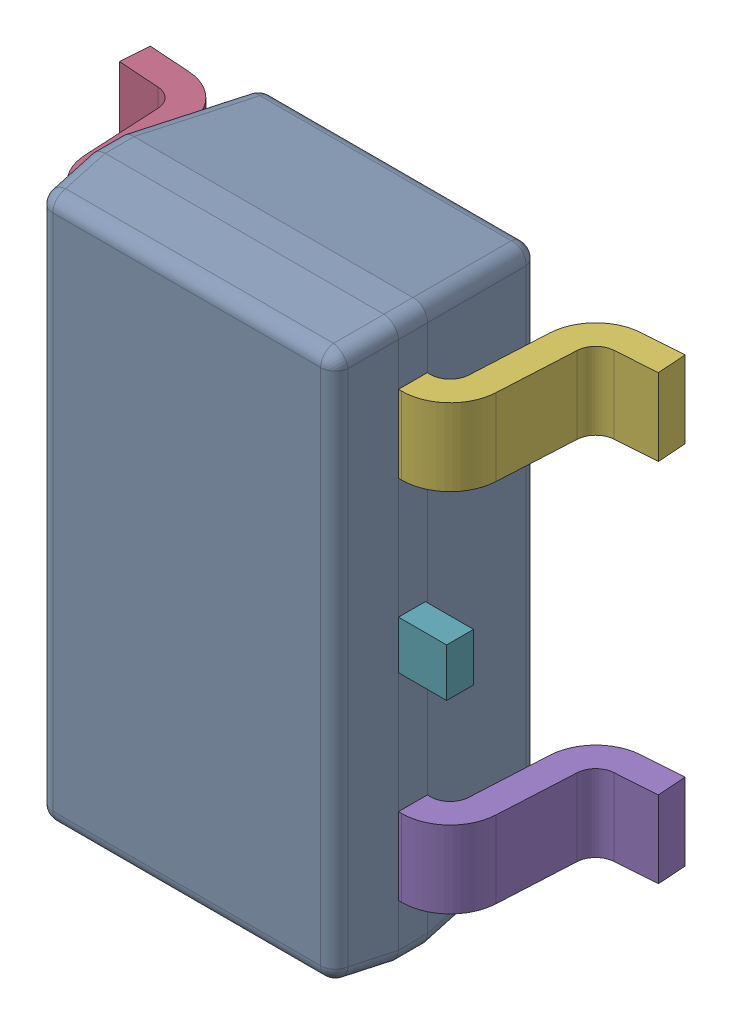
SolidWorks assembly 6348792768_1.step, configuration Default. Lengths in mm.
Overall size (2.8 2.9 1.2).
7 component instances, 3 part files, 0 mates.
Components (placement in the parent):
- BODY-SOT-1213_1.step-11: BODY-SOT-1213_1.step [Default] at (0 0 0.9) x (0 -1 0) z (-1 0 0) size (2.9 1.1 1.6)
- LEAD-SOT-1214_1.step-85: LEAD-SOT-1214_1.step [Default] at (-0.9395 -0.95 0.25) x (0 -1 0) z (-1 0 0) size (0.4 0.9 0.6)
- LEAD-SOT-1214_1.step-86: LEAD-SOT-1214_1.step [Default] at (-0.9395 0 0.25) x (0 -1 0) z (-1 0 0) size (0.4 0.9 0.6)
- LEAD-SOT-1214_1.step-87: LEAD-SOT-1214_1.step [Default] at (-0.9395 0.95 0.25) x (0 -1 0) z (-1 0 0) size (0.4 0.9 0.6)
- LEAD-SOT-1214_1.step-88: LEAD-SOT-1214_1.step [Default] at (0.9395 -0.95 0.25) x (0 1 0) z (1 0 0) size (0.4 0.9 0.6)
- LEAD-SOT-1214_1.step-89: LEAD-SOT-1214_1.step [Default] at (0.9395 0.95 0.25) x (0 1 0) z (1 0 0) size (0.4 0.9 0.6)
- LEAD-DUMMY-1215_1.step-11: LEAD-DUMMY-1215_1.step [Default] at (1.05 0 0.76) x (0 -1 0) z (-1 0 0) size (0.25 0.14 0.25)
